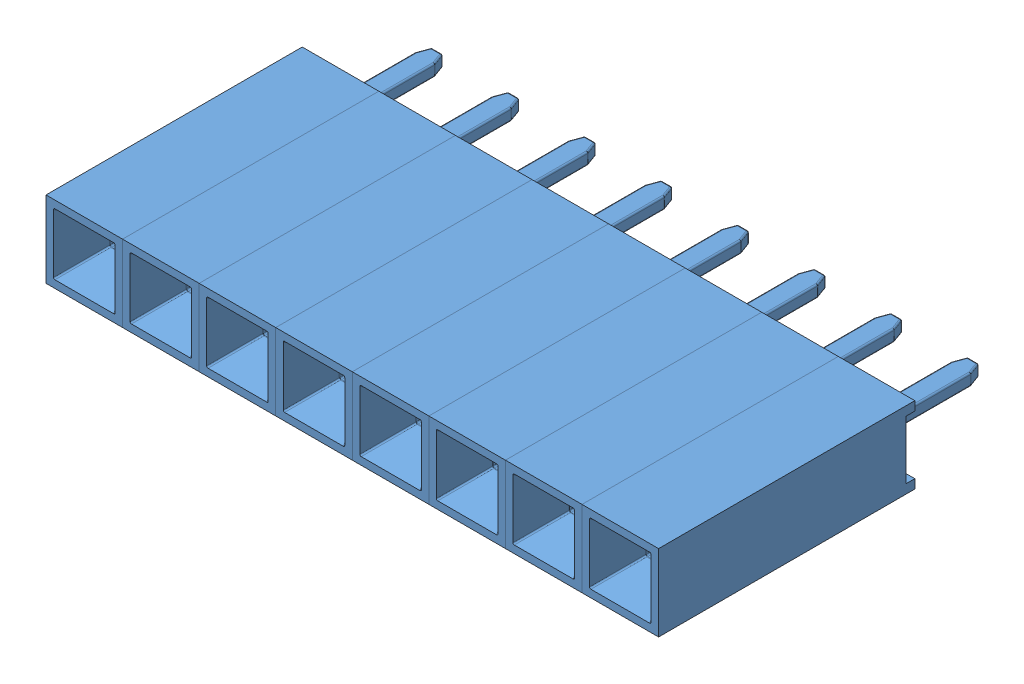
SolidWorks assembly Female Pin Header 01x08 Pitch 2.54mm Height 8.5mm.stp, configuration Valor predeterminado. Lengths in mm.
Overall size (20.32 2.54 11.7).
8 component instances, 1 part files, 0 mates.
Components (placement in the parent):
- Female Pin Header 1x.stp-1: Female Pin Header 1x.stp [Valor predeterminado] at origin size (2.54 2.54 11.7)
- Female Pin Header 1x.stp-2: Female Pin Header 1x.stp [Valor predeterminado] at (2.54 0 0) size (2.54 2.54 11.7)
- Female Pin Header 1x.stp-3: Female Pin Header 1x.stp [Valor predeterminado] at (5.08 0 0) size (2.54 2.54 11.7)
- Female Pin Header 1x.stp-4: Female Pin Header 1x.stp [Valor predeterminado] at (7.62 0 0) size (2.54 2.54 11.7)
- Female Pin Header 1x.stp-5: Female Pin Header 1x.stp [Valor predeterminado] at (10.16 0 0) size (2.54 2.54 11.7)
- Female Pin Header 1x.stp-6: Female Pin Header 1x.stp [Valor predeterminado] at (12.7 0 0) size (2.54 2.54 11.7)
- Female Pin Header 1x.stp-7: Female Pin Header 1x.stp [Valor predeterminado] at (15.24 0 0) size (2.54 2.54 11.7)
- Female Pin Header 1x.stp-8: Female Pin Header 1x.stp [Valor predeterminado] at (17.78 0 0) size (2.54 2.54 11.7)
